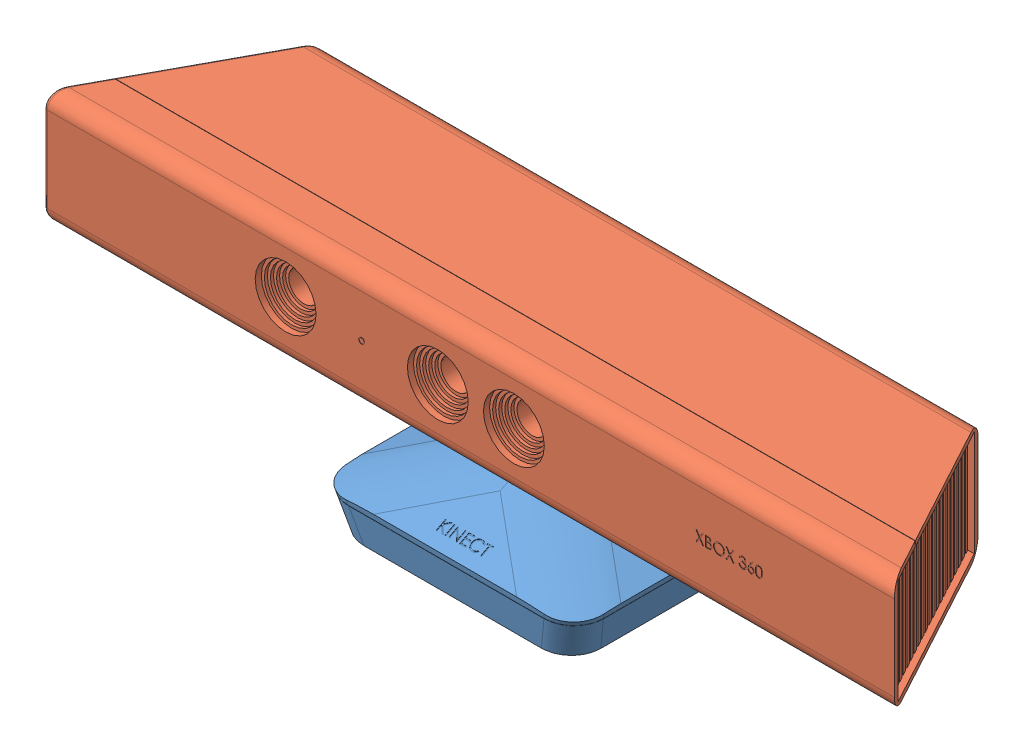
SolidWorks assembly final kinect, configuration Default. Lengths in mm.
Overall size (279.32 72.5 71.02).
2 component instances, 2 part files, 2 mates.
Components (placement in the parent):
- lower part-1: lower part [Default] at (2.1296 -16.1755 0.9636) size (86.05 27.21 71.02)
- kinect upper part-1: kinect upper part [Default] at (2.268 17.8245 -1.5083) size (279.32 60 60)
Mates (geometry in assembly coordinates):
- Concentric1: concentric: sphere of lower part-1; sphere of kinect upper part-1
- Parallel1: parallel: plane of lower part-1 through (-26.5143 -16.6755 23.2804) normal (0 -1 0); plane of kinect upper part-1 through (2.268 55.8245 -1.5083) normal (0 1 0)
